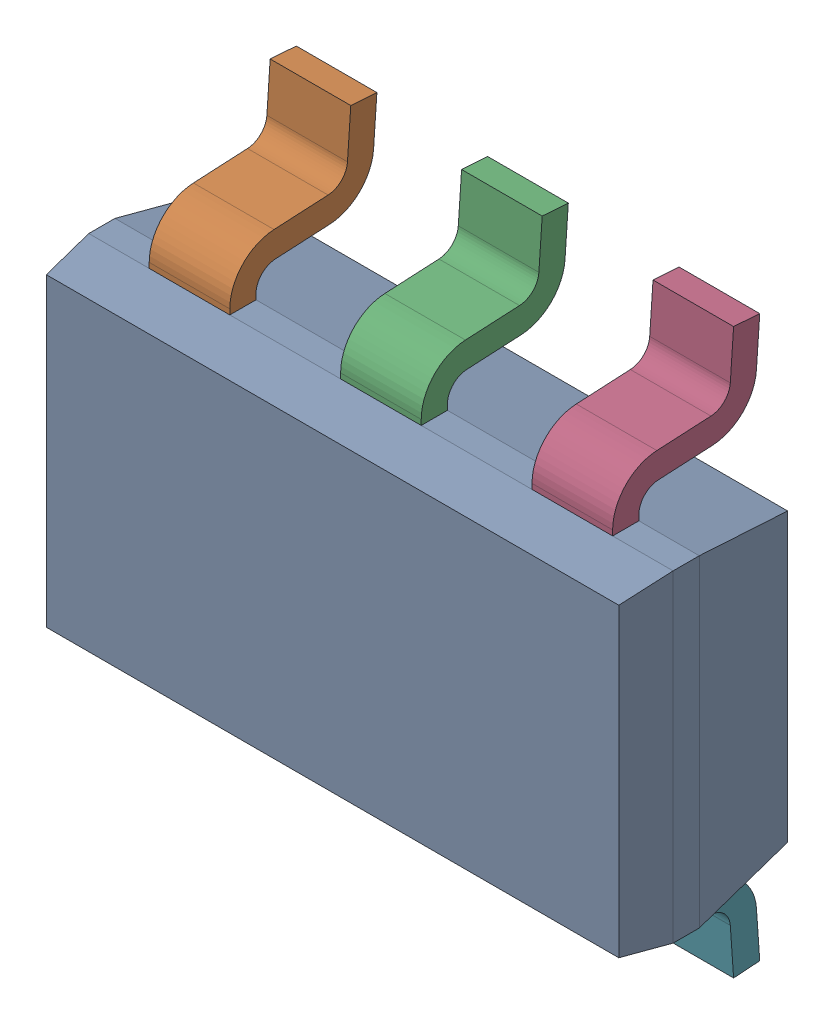
SolidWorks assembly U20, configuration ﾃﾞﾌｫﾙﾄ. Lengths in mm.
Overall size (2.9 2.8 0.97).
8 component instances, 2 part files, 0 mates.
Components (placement in the parent):
- DDC0006A-1: DDC0006A [ﾃﾞﾌｫﾙﾄ] at (27.94 15.875 0) x (0 1 0) z (0 0 1) size (2.8 2.9 0.97)
  - BODY-SOT-1: BODY-SOT [ﾃﾞﾌｫﾙﾄ] at (0 0 0.73) x (0 1 0) z (1 0 0) size (2.9 0.87 1.6)
  - LEAD-SOT-1: LEAD-SOT [ﾃﾞﾌｫﾙﾄ] at (0.9409 0.95 0.25) x (0 1 0) z (1 0 0) size (0.4 0.73 0.6)
  - LEAD-SOT-2: LEAD-SOT [ﾃﾞﾌｫﾙﾄ] at (0.9409 0 0.25) x (0 1 0) z (1 0 0) size (0.4 0.73 0.6)
  - LEAD-SOT-3: LEAD-SOT [ﾃﾞﾌｫﾙﾄ] at (0.9409 -0.95 0.25) x (0 1 0) z (1 0 0) size (0.4 0.73 0.6)
  - LEAD-SOT-4: LEAD-SOT [ﾃﾞﾌｫﾙﾄ] at (-0.9409 0.95 0.25) x (0 -1 0) z (-1 0 0) size (0.4 0.73 0.6)
  - LEAD-SOT-5: LEAD-SOT [ﾃﾞﾌｫﾙﾄ] at (-0.9409 0 0.25) x (0 -1 0) z (-1 0 0) size (0.4 0.73 0.6)
  - LEAD-SOT-6: LEAD-SOT [ﾃﾞﾌｫﾙﾄ] at (-0.9409 -0.95 0.25) x (0 -1 0) z (-1 0 0) size (0.4 0.73 0.6)
